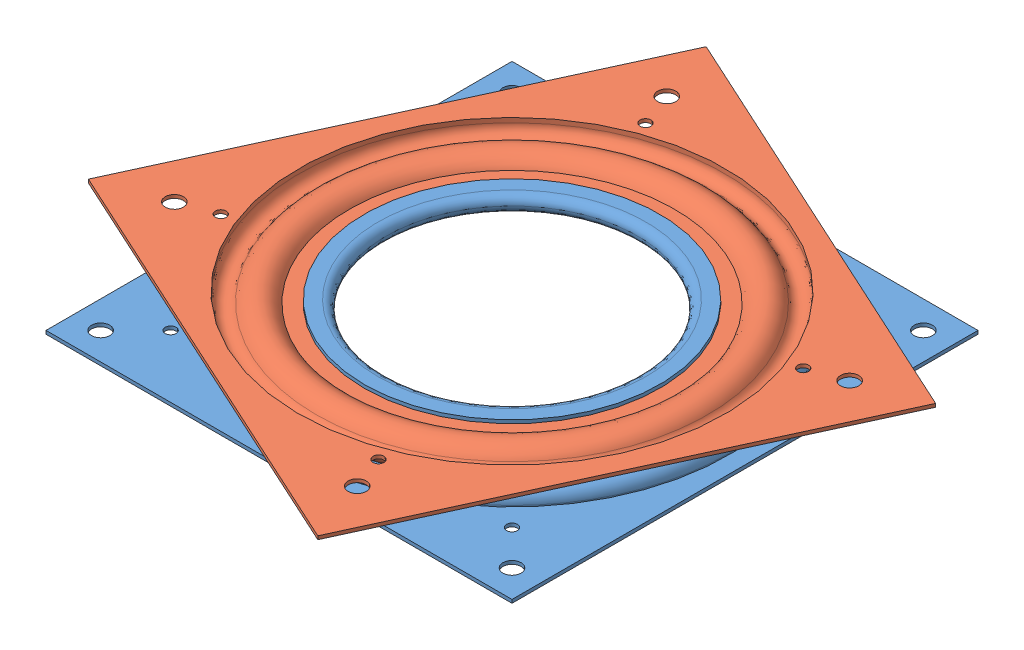
SolidWorks assembly 01 4inch Turntable Assembly, configuration Default. Lengths in mm.
Overall size (184.72 8.13 184.72).
2 component instances, 2 part files, 4 mates.
Components (placement in the parent):
- 4inch Turntable Bottom-1: 4inch Turntable Bottom [Default] at (0 4.826 0) size (101.6 6.6 101.6)
- 4inch Turntable Top-1: 4inch Turntable Top [Default] at (0 4.826 0) x (-0.937449 0 0.348122) z (-0.348122 0 -0.937449) size (143.68 3.78 143.68)
Mates (geometry in assembly coordinates):
- Hinge1: hinge anti-aligned: circle of 4inch Turntable Bottom-1; circle of 4inch Turntable Top-1; plane of 4inch Turntable Top-1 through (-27.3829 5.8674 10.1686) normal (0 1 0); plane of 4inch Turntable Bottom-1 through (32.1955 5.8674 0) normal (0 -1 0)
- Coincident1: coincident aligned: plane of 4inch Turntable Bottom-1 through (0 4.826 0) normal (1 0 0); plane of assembly through (0 0 0) normal (1 0 0)
- Coincident2: coincident anti-aligned: plane of 4inch Turntable Bottom-1 through (46.4273 0 0) normal (0 -1 0); plane of assembly through (0 0 0) normal (0 1 0)
- Coincident3: coincident aligned: plane of 4inch Turntable Bottom-1 through (0 4.826 0) normal (0 0 1); plane of assembly through (0 0 0) normal (0 0 1)
